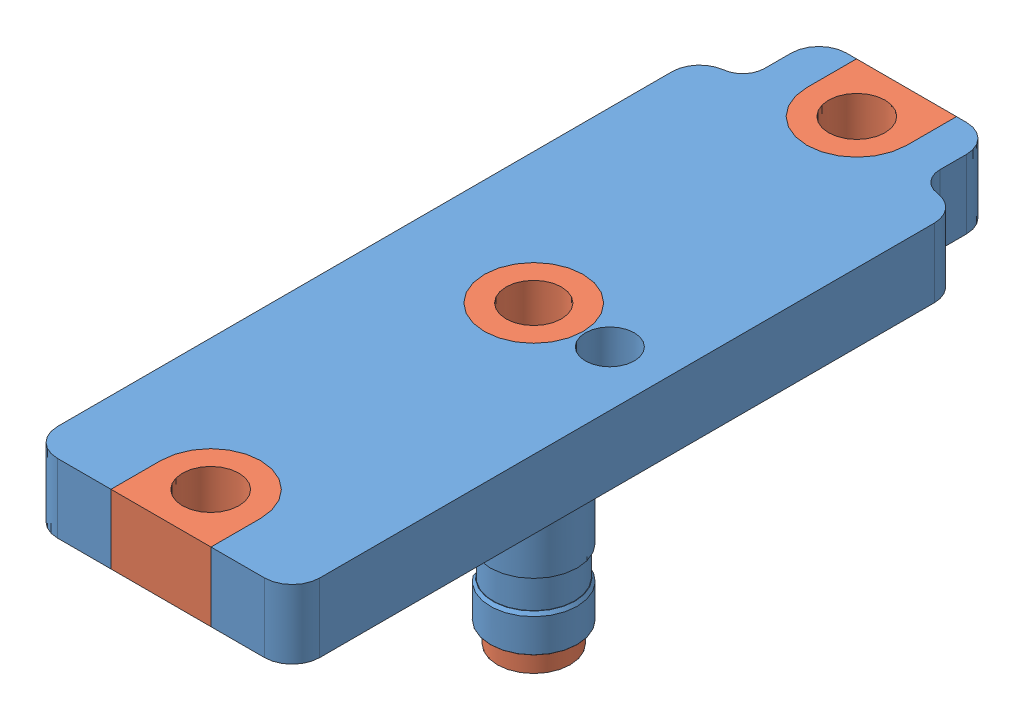
SolidWorks assembly New Mount Needle holder Assembly, configuration Default. Lengths in mm.
Overall size (24.28 27.15 68.58).
2 component instances, 2 part files, 2 mates.
Components (placement in the parent):
- New Mount Needle holder standard-1: New Mount Needle holder standard [Default] at origin size (24.28 25.21 68.58)
- New Mount Needle holder conductive-1: New Mount Needle holder conductive [Default] at origin size (11.82 27.15 68.58)
Mates (geometry in assembly coordinates):
- Coincident1: coincident aligned: plane of New Mount Needle holder standard-1 through (0 6.35 0) normal (0 1 0); plane of New Mount Needle holder conductive-1 through (0 6.35 0) normal (0 1 0)
- Concentric1: concentric anti-aligned: cylinder of New Mount Needle holder standard-1 through (12.065 6.35 -34.29) axis (0 1 0) radius 4.55; cylinder of New Mount Needle holder conductive-1 through (12.065 -20.8 -34.29) axis (0 -1 0) radius 2.55
